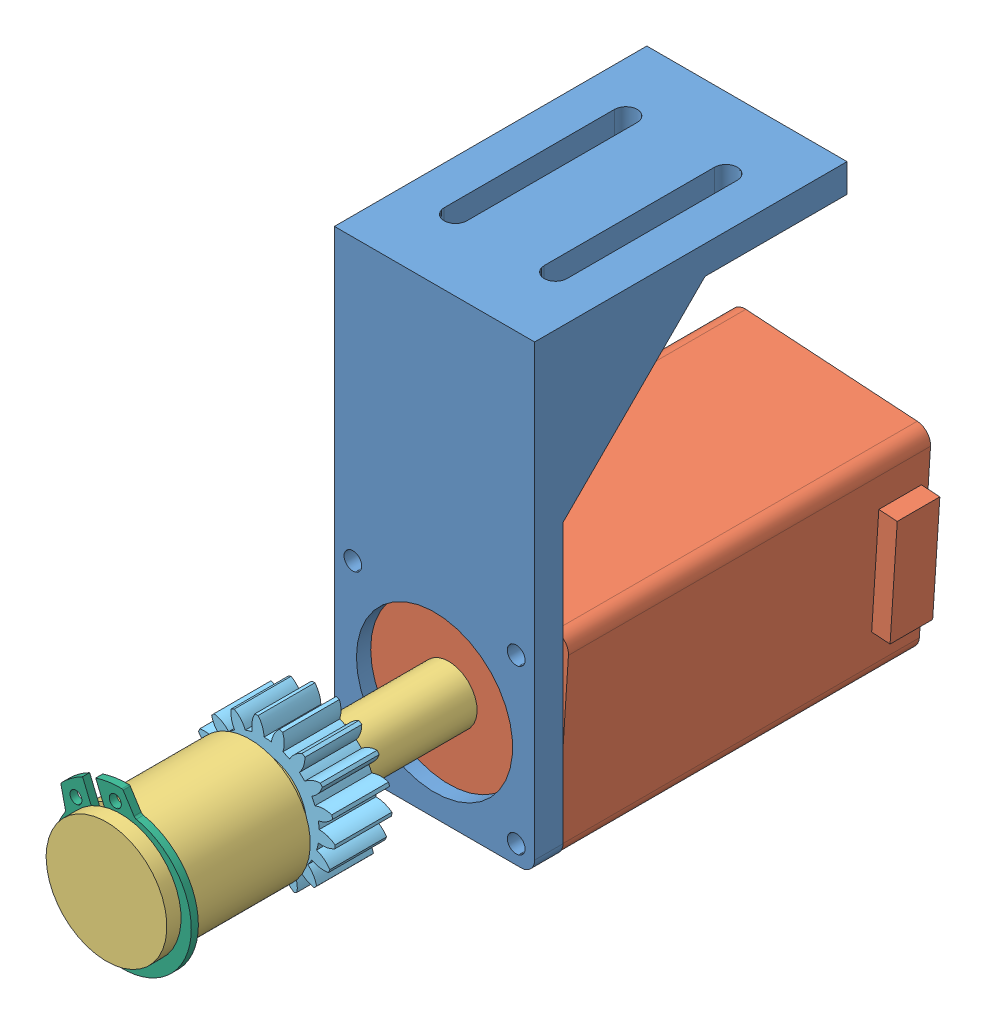
SolidWorks assembly 输出, configuration 默认. Lengths in mm.
Overall size (32.57 66.16 101.2).
6 component instances, 6 part files, 12 mates.
Components (placement in the parent):
- 电机支架-1: 电机支架 [默认] at (37.9391 -5.8951 18) size (28.2 65.1 44)
- 28步进-1: 28步进 [默认] at (38.2883 -8.0281 18) x (-0.065086 -0.99788 0) z (0 0 -1) size (28.2 30.8 71)
- 输出轴-1: 输出轴 [默认] at (38.2883 -8.0281 45) x (0.99788 -0.065086 0) z (0 0 -1) size (17 17 48.2)
- circlips for shaft--type a small gb-5: circlips for shaft--type a small gb [GB_CONNECTING_PIECE_RING_RRA 8] at (38.1852 -8.3415 37.2) x (0.949886 -0.312595 0) z (0 0 -1) size (9.38 11.87 0.8)
- spur gear_gb-2: spur gear_gb [GB - Spur gear 1M 18T 20PA 8FW ---S18A75H50L8.0S2] at (38.2883 -8.0281 46) x (0 0 -1) z (-0.99788 0.065086 0) size (8 19.78 20)
- circlips for shaft--type a large gb-2: circlips for shaft--type a large gb [GB_CONNECTING_PIECE_RING_RRA 17] at (38.5258 -8.6008 65.2) x (0.923728 0.383049 0) z (0 0 -1) size (19.4 21.93 1)
Mates (geometry in assembly coordinates):
- 同心1: concentric aligned: cylinder of 电机支架-1 through (38.2883 -8.0281 22) axis (0 0 -1) radius 11; cylinder of 28步进-1 through (38.2883 -8.0281 13.6257) axis (0 0 -1) radius 11
- 同心2: concentric anti-aligned: cylinder of 28步进-1 through (38.2883 -8.0281 31.6257) axis (0 0 -1) radius 2.5; cylinder of 输出轴-1 through (38.2883 -8.0281 39.6257) axis (0 0 1) radius 2.5
- 重合4: coincident anti-aligned: plane of 28步进-1 through (36.3902 -6.4011 31.6257) normal (-0.99788 0.065086 0); plane of 输出轴-1 through (36.2926 -7.8979 39.6257) normal (0.99788 -0.065086 0)
- 重合5: coincident anti-aligned: plane of 28步进-1 through (38.2883 -8.0281 13.6257) normal (0 0 1); plane of 输出轴-1 through (38.2883 -8.0281 13.6257) normal (0 0 -1)
- 同心6: concentric anti-aligned: cylinder of 输出轴-1 through (38.2883 -8.0281 39.6257) axis (0 0 1) radius 4; cylinder of circlips for shaft--type a small gb-5 through (38.2883 -8.0281 31.6257) axis (0 0 -1) radius 3.7
- 重合6: coincident anti-aligned: plane of 输出轴-1 through (38.2883 -8.0281 31.6257) normal (0 0 -1); plane of circlips for shaft--type a small gb-5 through (39.3598 -2.8526 31.6257) normal (0 0 1)
- 同心7: concentric anti-aligned: cylinder of 输出轴-1 through (38.2883 -8.0281 39.6257) axis (0 0 -1) radius 4; cylinder of spur gear_gb-2 through (38.2883 -8.0281 -10.3744) axis (0 0 1) radius 4
- 重合7: coincident anti-aligned: plane of 输出轴-1 through (36.7915 -7.9304 39.6257) normal (-0.99788 0.065086 0); plane of spur gear_gb-2 through (36.7915 -7.9304 -10.3744) normal (0.99788 -0.065086 0)
- 重合8: coincident anti-aligned: plane of 输出轴-1 through (38.2883 -8.0281 39.6257) normal (0 0 -1); plane of spur gear_gb-2 through (38.2883 -8.0281 39.6257) normal (0 0 1)
- 同心8: concentric aligned: cylinder of 输出轴-1 through (38.2883 -8.0281 61.8257) axis (0 0 -1) radius 8.5; cylinder of circlips for shaft--type a large gb-2 through (38.2883 -8.0281 59.8257) axis (0 0 -1) radius 7.85
- 重合9: coincident anti-aligned: plane of 输出轴-1 through (37.7774 -15.8614 58.8257) normal (0 0 1); plane of circlips for shaft--type a large gb-2 through (38.2883 -8.0281 58.8257) normal (0 0 -1)
- 重合11: coincident anti-aligned: plane of 电机支架-1 through (26.0885 -20.2279 18) normal (0 0 -1); plane of 28步进-1 through (38.2883 -8.0281 18) normal (0 0 1)
